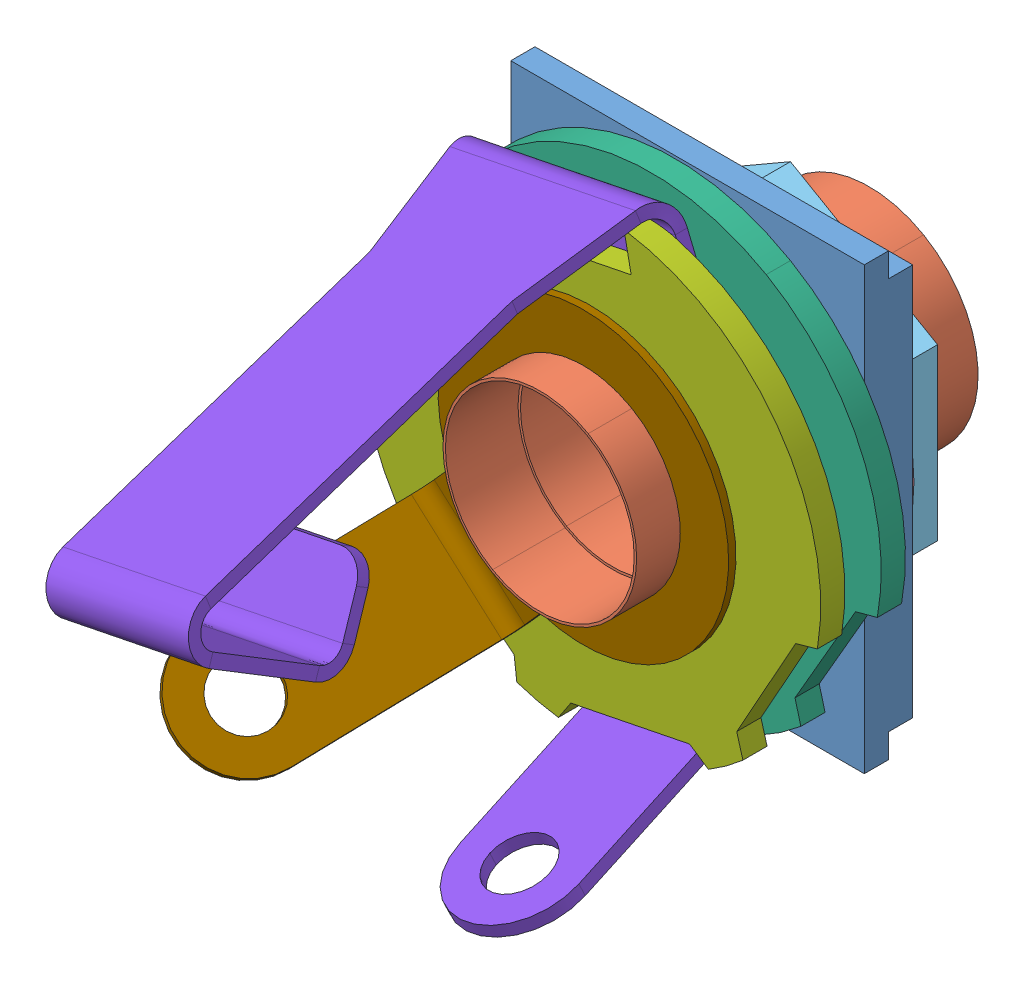
SolidWorks assembly Keystone-6,35, configuration Standard. Lengths in mm.
Overall size (26.22 31.79 30.76).
10 component instances, 9 part files, 3 mates.
Components (placement in the parent):
- Keystone-Loch-1: Keystone-Loch [Standard] at (0.2898 -8.4607 17.2) size (14.6 18.2 2)
- Jack6_3-1: Jack6_3 [Standard] at (-0.9352 -7.3755 11.7) x (0 1 0) z (0 0 -1) size (31.79 26.22 30.76)
  - Jack-6,35-Body-1: Jack-6,35-Body [Standard] at (7.0148 -6.075 0) x (0.866025 0.5 0) z (0 0 1) size (9 9 13.6)
  - Jack-6,35-Washer-1: Jack-6,35-Washer [Standard] at (7.0148 -6.075 -8) x (0.866025 0.5 0) z (0 0 1) size (16 16 0.5)
  - Jack-6,35-Washer-Outer-3: Jack-6,35-Washer-Outer [Standard] at (7.0148 -6.075 -5.5) x (0.866025 0.5 0) z (0 0 1) size (14 14 0.35)
  - Jack-6,35-Nut-1: Jack-6,35-Nut [Standard] at (7.0148 -6.075 -5.15) x (0.866025 0.5 0) z (0 0 1) size (12.15 14.03 1.9)
  - Jack-6,35-Housing-Outer-2: Jack-6,35-Housing-Outer [Standard] at (7.0148 -6.075 -9) x (0.866025 0.5 0) z (0 0 1) size (19 18.46 2)
  - Jack-6,35-Washer-Inner-1: Jack-6,35-Washer-Inner [Standard] at (7.0148 -6.075 -11.5) x (-0.61771 0.786406 0) z (0 0 1) size (18.84 18.46 1)
  - Jack-6,35-Connector-Tip-1: Jack-6,35-Connector-Tip [Standard] at (43.5437 -13.4084 -14.3779) x (-0.196829 -0.980438 0) z (-0.803128 0.161233 0.573576) size (14 19.8 22.29)
  - Jack-6,35-Connector-Ground-1: Jack-6,35-Connector-Ground [Standard] at (7.0148 -6.075 -11.8) x (0.664833 -0.746992 0) z (0 0 -1) size (12 16.84 10.14)
Mates (geometry in assembly coordinates):
- Konzentrisch1: concentric aligned: cylinder of Keystone-Loch-1 through (-7.0102 -0.3607 27.2) axis (0 0 -1) radius 4.5; cylinder of Jack6_3-1/Jack-6,35-Body-1 through (-7.0102 -0.3607 19.2) axis (0 0 -1) radius 4.5
- Deckungsgleich1: coincident anti-aligned: plane of Keystone-Loch-1 through (0.2898 -8.4607 19.2) normal (0 0 1); plane of Jack6_3-1/Jack-6,35-Washer-1 through (-7.0102 -0.3607 19.2) normal (0 0 -1)
- Parallel1: parallel aligned: plane of Keystone-Loch-1 through (0.2898 -8.4607 18.2) normal (1 0 0); plane of Jack6_3-1/Jack-6,35-Nut-1 through (-0.9352 3.1467 14.95) normal (1 0 0)
